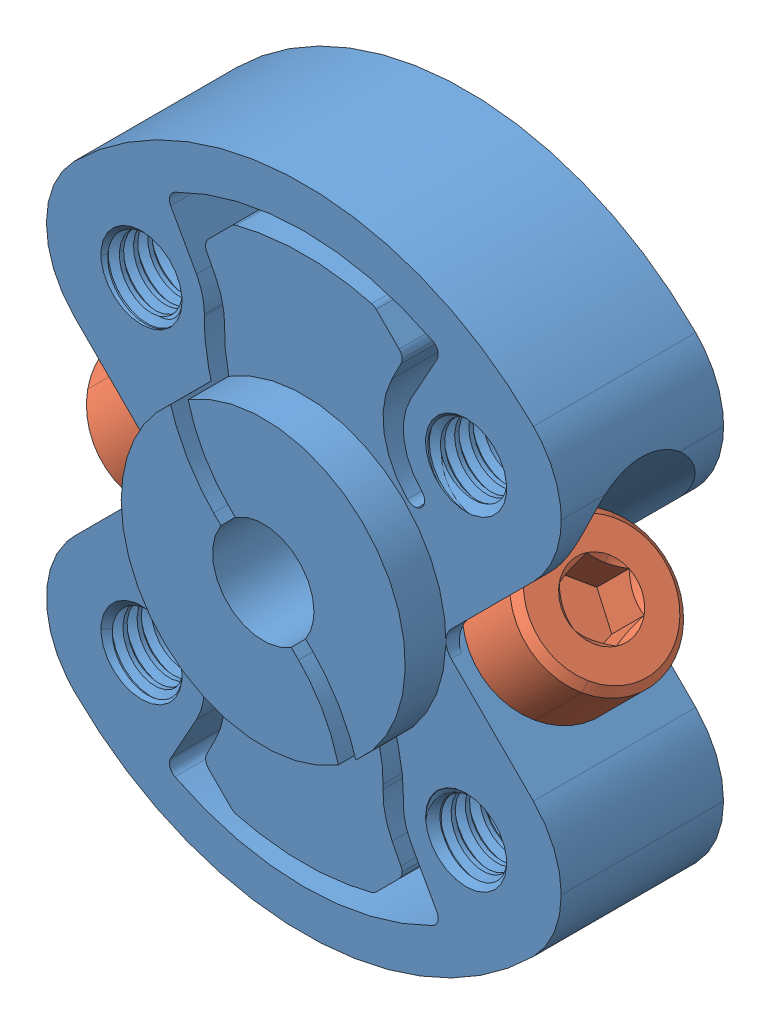
SolidWorks assembly 5mm Hub 1309-0016-0005, configuration Default. Lengths in mm.
Overall size (28.36 32 10.95).
3 component instances, 2 part files, 0 mates.
Components (placement in the parent):
- 1309-0016-0005.STEP-1: 1309-0016-0005.STEP [Default] at (-14.5586 4.6088 4.1124) size (25.38 32 10)
- 2800-0004-0014_90128A207.STEP-1: 2800-0004-0014_90128A207.STEP [Default] at (-16.6115 -6.5099 4.1124) x (0.5 -0.5 0.707107) z (-0.707107 -0.707107 0) size (7 7 18.01)
- 2800-0004-0014_90128A207.STEP-2: 2800-0004-0014_90128A207.STEP [Default] at (-12.5058 15.7276 4.1124) x (-0.5 0.5 0.707107) z (0.707107 0.707107 0) size (7 7 18.01)
